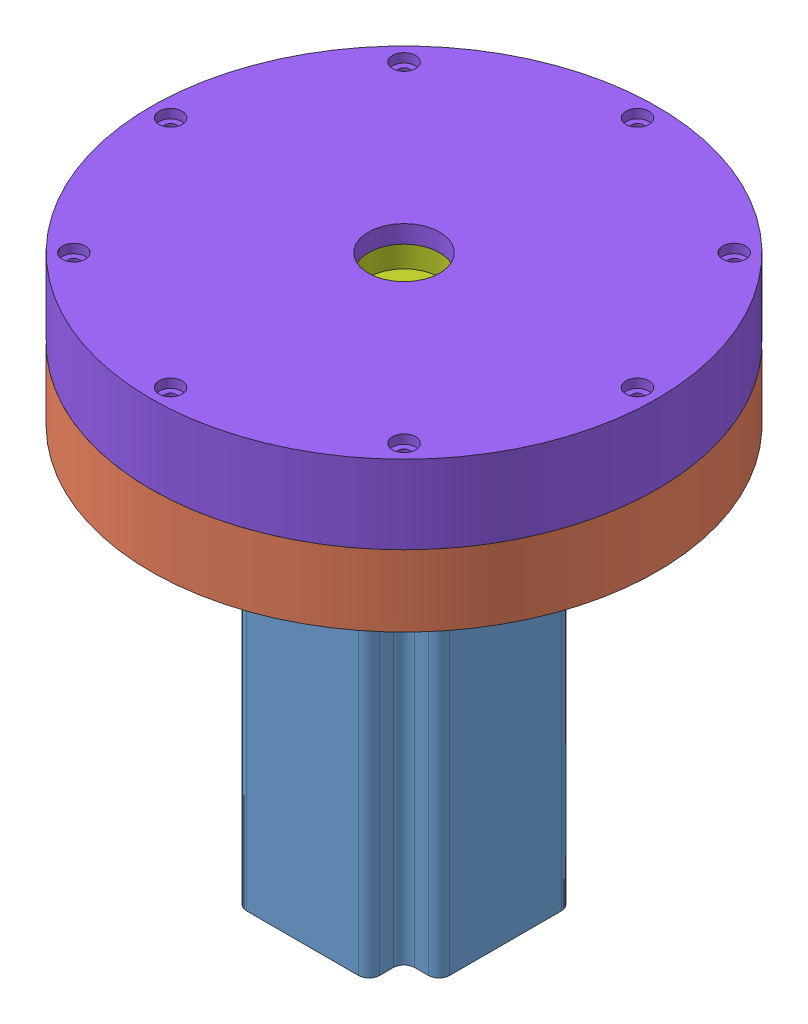
SolidWorks assembly Nema 23 112mm, configuration Default. Lengths in mm.
Overall size (200.82 153.53 200.82).
8 component instances, 8 part files, 17 mates.
Components (placement in the parent):
- NEMA23 112mm-1: NEMA23 112mm [Default] at (58.008 21.0769 133.8479) size (57 135.53 57)
- 112mm ring gear-2: 112mm ring gear [Default] at (58.008 142.6069 133.8479) x (1 0 0) z (0 1 0) size (142 142 20)
- 112mm sun gear-1: 112mm sun gear [Default] at (58.008 152.6069 133.8479) x (0.59919 0 -0.800607) z (0 -1 0) size (38.1 38.1 28.4)
- 112mm planet gear-3: 112mm planet gear [Default] at (87.0882 152.6069 139.9252) x (-0.161839 0 -0.986817) z (0 1 0) size (43.6 43.6 20)
- 112mm planet gear 2 off-1: 112mm planet gear 2 off [Default] at (38.0109 147.6069 111.4846) x (0.469267 0 0.883057) z (0 1 0) size (44 44 20)
- 112mm planet gear 1 off-1: 112mm planet gear 1 off [Default] at (48.6786 147.6069 162.3603) x (-0.894863 0 -0.44634) z (0 1 0) size (43.98 43.98 20)
- 112mm input strain gear-1: 112mm input strain gear [Default] at (58.008 162.6069 133.8479) x (0.996284 0 0.086133) z (0 -1 0) size (120 120 17)
- strain gear fixator-1: strain gear fixator [Default] at (58.008 152.6069 133.8479) x (-0.707107 0 -0.707107) z (0 1 0) size (142 142 22)
Mates (geometry in assembly coordinates):
- Coincident5: coincident anti-aligned: plane of NEMA23 112mm-1 through (33.508 132.6069 158.3479) normal (0 1 0); plane of 112mm ring gear-2 through (58.008 132.6069 133.8479) normal (0 -1 0)
- Concentric19: concentric anti-aligned: cylinder of NEMA23 112mm-1 through (58.008 156.6069 133.8479) axis (0 -1 0) radius 5; cylinder of 112mm ring gear-2 through (58.008 132.6069 133.8479) axis (0 1 0) radius 19.05
- Concentric20: concentric aligned: cylinder of NEMA23 112mm-1 through (81.508 25.4069 110.3479) axis (0 1 0) radius 2.5; cylinder of 112mm ring gear-2 through (81.508 132.6069 110.3479) axis (0 1 0) radius 2
- Coincident6: coincident anti-aligned: plane of NEMA23 112mm-1 through (58.008 134.2069 133.8479) normal (0 1 0); plane of 112mm sun gear-1 through (58.008 134.2069 133.8479) normal (0 -1 0)
- Parallel9: parallel aligned: plane of NEMA23 112mm-1 through (58.008 136.6069 129.3479) normal (0 0 -1); plane of 112mm sun gear-1 through (55.8286 156.6069 138.3479) normal (0 0 -1)
- Concentric23: concentric aligned: cylinder of 112mm ring gear-2 through (58.008 132.6069 133.8479) axis (0 1 0) radius 19.05; cylinder of 112mm sun gear-1 through (58.008 134.2069 133.8479) axis (0 1 0) radius 19.05
- Coincident15: coincident: point of assembly; point of 112mm planet gear 1 off-1; circle of assembly
- Coincident17: coincident anti-aligned: plane of 112mm ring gear-2 through (58.008 142.6069 133.8479) normal (0 1 0); plane of 112mm planet gear 1 off-1 through (48.6786 142.6069 162.3603) normal (0 -1 0)
- Coincident18: coincident: unknown of 112mm planet gear 2 off-1
- Coincident19: coincident anti-aligned: plane of 112mm ring gear-2 through (58.008 142.6069 133.8479) normal (0 1 0); plane of 112mm planet gear 2 off-1 through (38.0109 142.6069 111.4846) normal (0 -1 0)
- Coincident20: coincident anti-aligned: plane of 112mm ring gear-2 through (58.008 152.6069 133.8479) normal (0 1 0); plane of 112mm input strain gear-1 through (58.008 152.6069 133.8479) normal (0 -1 0)
- Concentric25: concentric anti-aligned: cylinder of 112mm ring gear-2 through (103.5906 152.6069 117.5504) axis (0 -1 0) radius 6.2753; cylinder of 112mm input strain gear-1 through (103.5906 152.6069 117.5504) axis (0 1 0) radius 6.2753
- Concentric27: concentric anti-aligned: cylinder of 112mm ring gear-2 through (58.008 152.6069 133.8479) axis (0 -1 0) radius 71; cylinder of 112mm input strain gear-1 through (58.008 152.6069 133.8479) axis (0 1 0) radius 60
- Coincident23: coincident anti-aligned: plane of 112mm ring gear-2 through (58.008 152.6069 133.8479) normal (0 1 0); plane of strain gear fixator-1 through (58.008 152.6069 133.8479) normal (0 -1 0)
- Concentric28: concentric aligned: cylinder of 112mm ring gear-2 through (58.008 152.6069 133.8479) axis (0 -1 0) radius 71; cylinder of strain gear fixator-1 through (58.008 169.6069 133.8479) axis (0 -1 0) radius 71
- Concentric29: concentric anti-aligned: cylinder of 112mm ring gear-2 through (123.508 152.6069 133.8479) axis (0 -1 0) radius 1.637; cylinder of strain gear fixator-1 through (123.508 152.6069 133.8479) axis (0 1 0) radius 1.637
- Coincident26: coincident anti-aligned: plane of 112mm ring gear-2 through (58.008 142.6069 133.8479) normal (0 1 0); plane of 112mm planet gear-3 through (87.0882 142.6069 139.9252) normal (0 -1 0)
